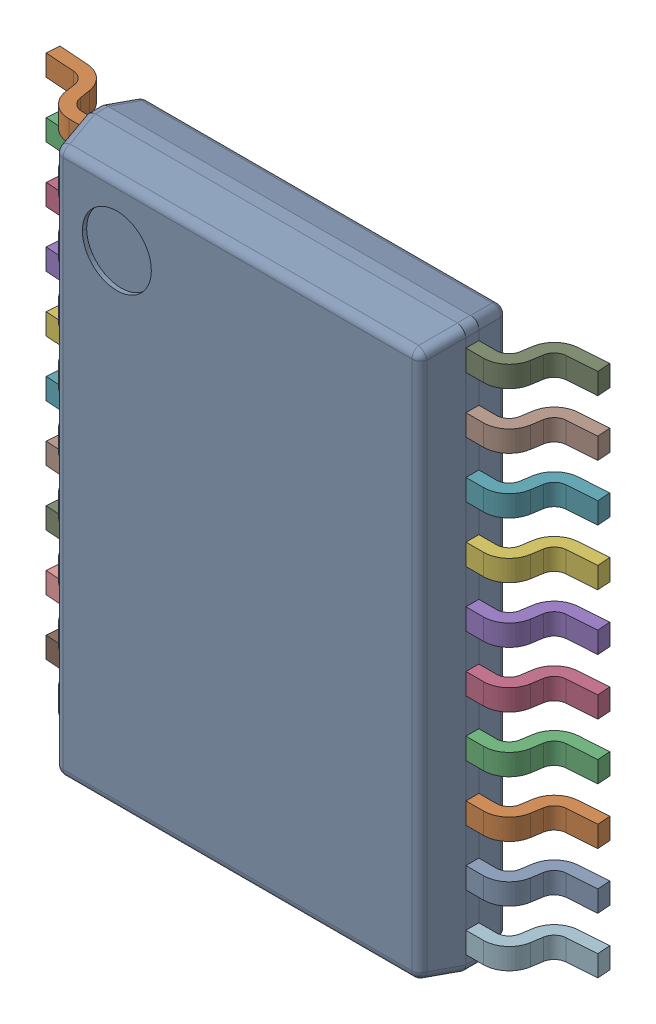
SolidWorks assembly IC14_1.step, configuration Default. Lengths in mm.
Overall size (6.4 6.5 1.13).
22 component instances, 2 part files, 0 mates.
Components (placement in the parent):
- 9651432272_1.step-3: 9651432272_1.step [Default] at (484.632 272.258 0) size (6.4 6.5 1.13)
  - BODY-TSSOP_1.step-3: BODY-TSSOP_1.step [Default] at (0 0 0.68) x (1 0 0) z (0 -1 0) size (4.4 1 6.5)
  - LEAD-TSSOP_1.step-66: LEAD-TSSOP_1.step [Default] at (-2.575 2.925 0.25) x (0 -1 0) z (-1 0 0) size (0.24 0.68 1)
  - LEAD-TSSOP_1.step-67: LEAD-TSSOP_1.step [Default] at (-2.575 2.275 0.25) x (0 -1 0) z (-1 0 0) size (0.24 0.68 1)
  - LEAD-TSSOP_1.step-68: LEAD-TSSOP_1.step [Default] at (-2.575 1.625 0.25) x (0 -1 0) z (-1 0 0) size (0.24 0.68 1)
  - LEAD-TSSOP_1.step-69: LEAD-TSSOP_1.step [Default] at (-2.575 0.975 0.25) x (0 -1 0) z (-1 0 0) size (0.24 0.68 1)
  - LEAD-TSSOP_1.step-70: LEAD-TSSOP_1.step [Default] at (-2.575 0.325 0.25) x (0 -1 0) z (-1 0 0) size (0.24 0.68 1)
  - LEAD-TSSOP_1.step-71: LEAD-TSSOP_1.step [Default] at (-2.575 -0.325 0.25) x (0 -1 0) z (-1 0 0) size (0.24 0.68 1)
  - LEAD-TSSOP_1.step-72: LEAD-TSSOP_1.step [Default] at (-2.575 -0.975 0.25) x (0 -1 0) z (-1 0 0) size (0.24 0.68 1)
  - LEAD-TSSOP_1.step-73: LEAD-TSSOP_1.step [Default] at (-2.575 -1.625 0.25) x (0 -1 0) z (-1 0 0) size (0.24 0.68 1)
  - LEAD-TSSOP_1.step-74: LEAD-TSSOP_1.step [Default] at (-2.575 -2.275 0.25) x (0 -1 0) z (-1 0 0) size (0.24 0.68 1)
  - LEAD-TSSOP_1.step-75: LEAD-TSSOP_1.step [Default] at (-2.575 -2.925 0.25) x (0 -1 0) z (-1 0 0) size (0.24 0.68 1)
  - LEAD-TSSOP_1.step-76: LEAD-TSSOP_1.step [Default] at (2.575 -2.925 0.25) x (0 1 0) z (1 0 0) size (0.24 0.68 1)
  - LEAD-TSSOP_1.step-77: LEAD-TSSOP_1.step [Default] at (2.575 -2.275 0.25) x (0 1 0) z (1 0 0) size (0.24 0.68 1)
  - LEAD-TSSOP_1.step-78: LEAD-TSSOP_1.step [Default] at (2.575 -1.625 0.25) x (0 1 0) z (1 0 0) size (0.24 0.68 1)
  - LEAD-TSSOP_1.step-79: LEAD-TSSOP_1.step [Default] at (2.575 -0.975 0.25) x (0 1 0) z (1 0 0) size (0.24 0.68 1)
  - LEAD-TSSOP_1.step-80: LEAD-TSSOP_1.step [Default] at (2.575 -0.325 0.25) x (0 1 0) z (1 0 0) size (0.24 0.68 1)
  - LEAD-TSSOP_1.step-81: LEAD-TSSOP_1.step [Default] at (2.575 0.325 0.25) x (0 1 0) z (1 0 0) size (0.24 0.68 1)
  - LEAD-TSSOP_1.step-82: LEAD-TSSOP_1.step [Default] at (2.575 0.975 0.25) x (0 1 0) z (1 0 0) size (0.24 0.68 1)
  - LEAD-TSSOP_1.step-83: LEAD-TSSOP_1.step [Default] at (2.575 1.625 0.25) x (0 1 0) z (1 0 0) size (0.24 0.68 1)
  - LEAD-TSSOP_1.step-84: LEAD-TSSOP_1.step [Default] at (2.575 2.275 0.25) x (0 1 0) z (1 0 0) size (0.24 0.68 1)
  - LEAD-TSSOP_1.step-85: LEAD-TSSOP_1.step [Default] at (2.575 2.925 0.25) x (0 1 0) z (1 0 0) size (0.24 0.68 1)
